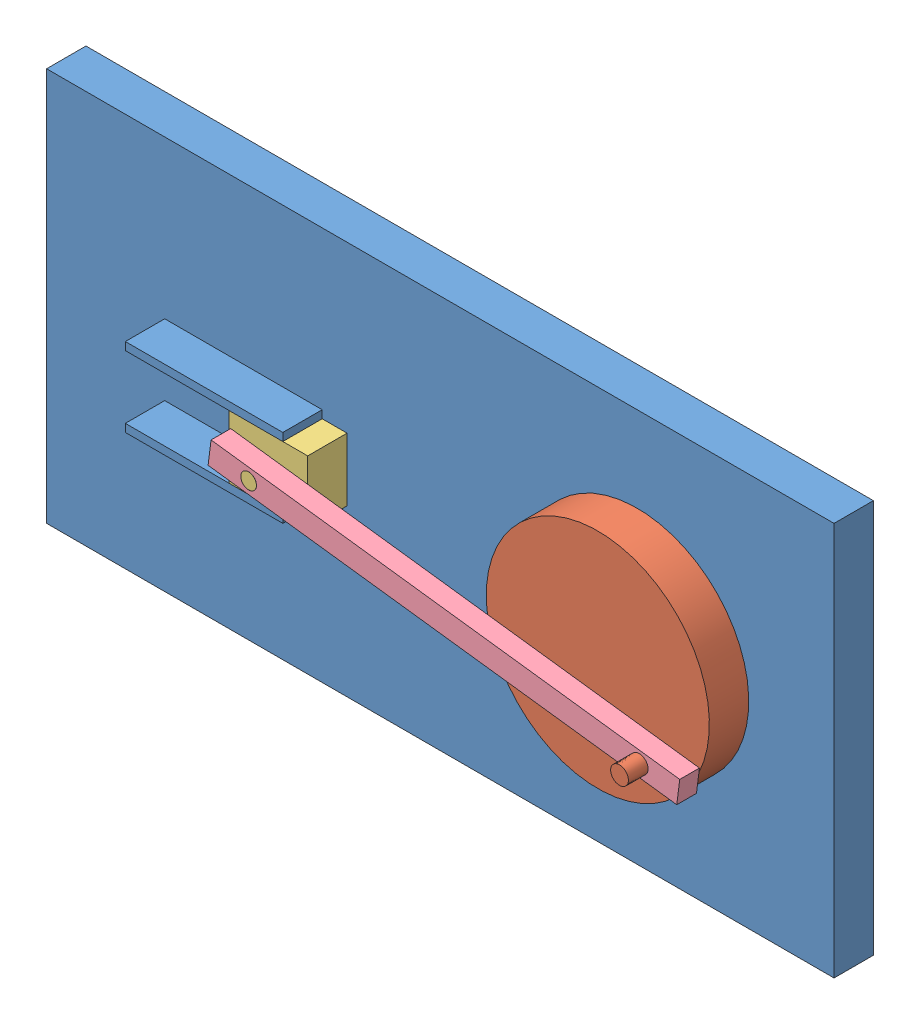
SolidWorks assembly Assem1, configuration Default. Lengths in mm.
Overall size (200 100 30).
4 component instances, 4 part files, 7 mates.
Components (placement in the parent):
- Part1-1: Part1 [Default] at (83.635 104.7898 148.4937) size (200 100 20)
- Part2-3: Part2 [Default] at (133.635 104.7898 158.4937) x (-0.775762 0.631026 0) z (0 0 1) size (56.67 56.67 30)
- Part3-1: Part3 [Default] at (49.9498 104.7898 158.4937) size (20 16 15)
- Part4-1: Part4 [Default] at (99.55 98.4796 168.4937) x (0.992004 -0.126205 0) z (0 0 1) size (120 6 5)
Mates (geometry in assembly coordinates):
- Concentric2: concentric aligned: cylinder of Part1-1 through (133.635 104.7898 158.4937) axis (0 0 -1) radius 2; cylinder of Part2-3 through (133.635 104.7898 168.4937) axis (0 0 -1) radius 2.267
- Coincident2: coincident anti-aligned: plane of Part1-1 through (83.635 104.7898 158.4937) normal (0 0 1); plane of Part2-3 through (133.635 104.7898 158.4937) normal (0 0 -1)
- Coincident3: coincident anti-aligned: plane of Part1-1 through (83.635 104.7898 158.4937) normal (0 0 1); plane of Part3-1 through (49.9498 104.7898 158.4937) normal (0 0 -1)
- Coincident4: coincident anti-aligned: plane of Part1-1 through (13.635 112.7898 168.4937) normal (0 -1 0); plane of Part3-1 through (39.9498 112.7898 168.4937) normal (0 1 0)
- Coincident5: coincident anti-aligned: cylinder of Part3-1 through (49.9498 104.7898 173.4937) axis (0 0 -1) radius 2; circle of Part4-1
- Concentric3: concentric aligned: cylinder of Part2-3 through (149.1502 92.1693 178.4937) axis (0 0 -1) radius 2.267; cylinder of Part4-1 through (149.1502 92.1693 173.4937) axis (0 0 -1) radius 2
- Coincident6: coincident anti-aligned: plane of Part2-3 through (133.635 104.7898 168.4937) normal (0 0 1); plane of Part4-1 through (99.55 98.4796 168.4937) normal (0 0 -1)
